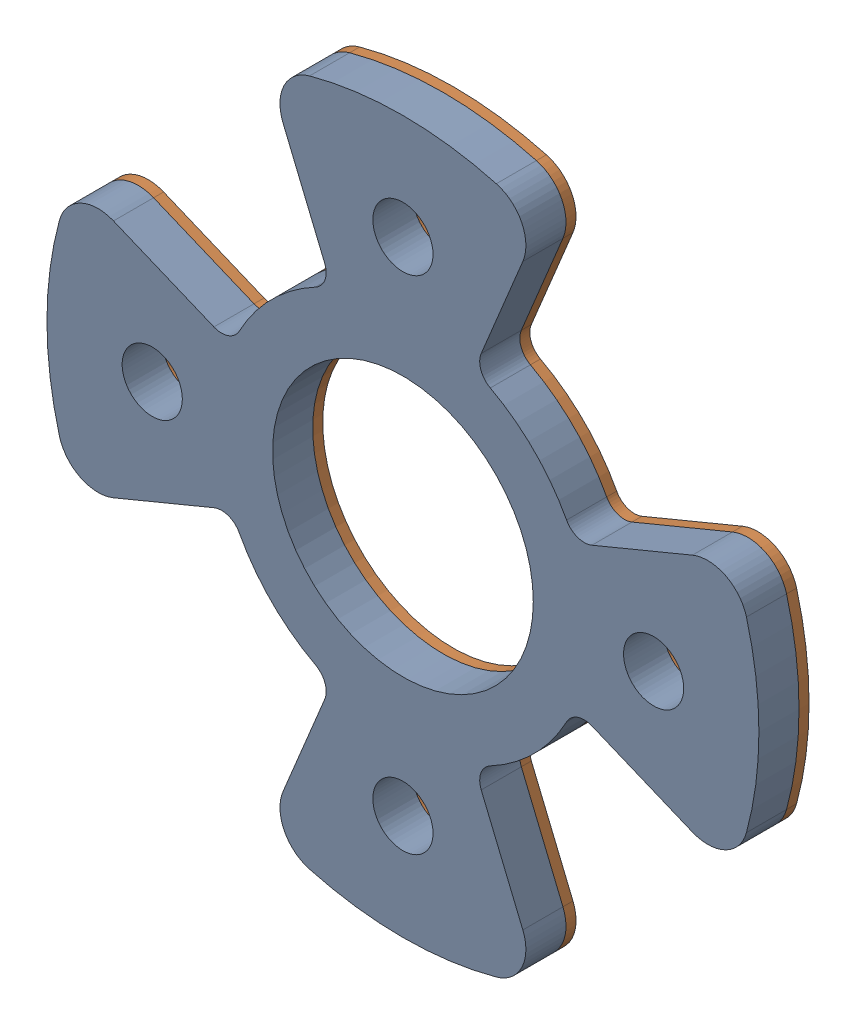
SolidWorks assembly Spacers_1, configuration Default. Lengths in mm.
Overall size (35.5 35.5 2.5).
2 component instances, 2 part files, 0 mates.
Components (placement in the parent):
- PCB_1-1: PCB_1 [Default] at (-11.099 -71.9658 -4) size (35.5 35.5 2)
- Steel_1-1: Steel_1 [Default] at (-11.099 -71.9658 -4.5) size (35.5 35.5 0.5)
